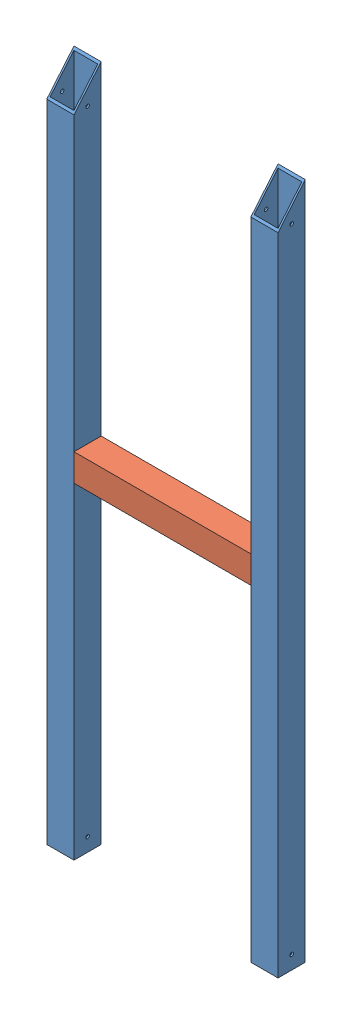
SolidWorks assembly GE-18077, configuration Default. Lengths in mm.
Overall size (431.8 1265.65 50.8).
3 component instances, 2 part files, 9 mates.
Components (placement in the parent):
- GE-18077-1-1: GE-18077-1 [Default] at (381 1434.7107 -127) x (0 -1 0) z (0 0 1) size (1265.65 50.8 50.8)
- GE-18077-1-2: GE-18077-1 [Default] at (0 1434.7107 -127) x (0 -1 0) z (0 0 1) size (1265.65 50.8 50.8)
- GE-18077-2-1: GE-18077-2 [Default] at (0 1434.7107 -127) x (0 -1 0) z (0 0 1) size (50.8 330.2 50.8)
Mates (geometry in assembly coordinates):
- Distance1: distance = 609.6 mm aligned: plane of GE-18077-2-1 through (165.1 609.6 25.4) normal (0 -1 0); plane of GE-18077-1-2 through (-215.9 0 1029.6131) normal (0 -1 0)
- Coincident2: coincident aligned: plane of GE-18077-1-2 through (-215.9 951.4898 50.8) normal (0 0 1); plane of GE-18077-2-1 through (165.1 951.4898 50.8) normal (0 0 1)
- Coincident3: coincident anti-aligned: plane of GE-18077-1-2 through (-165.1 933.0531 510.6552) normal (1 0 0); plane of GE-18077-2-1 through (-165.1 836.2206 25.4) normal (-1 0 0)
- Coincident4: coincident anti-aligned: plane of GE-18077-1-1 through (165.1 933.0531 510.6552) normal (-1 0 0); plane of GE-18077-2-1 through (165.1 836.2206 25.4) normal (1 0 0)
- Coincident5: coincident aligned: plane of GE-18077-1-1 through (165.1 951.4898 50.8) normal (0 0 1); plane of GE-18077-2-1 through (165.1 951.4898 50.8) normal (0 0 1)
- Coincident6: coincident aligned: plane of GE-18077-1-1 through (165.1 203.3958 1029.6131) normal (0 -1 0); plane of GE-18077-1-2 through (-215.9 203.3958 1029.6131) normal (0 -1 0)
- Coincident7: coincident anti-aligned: plane of ? through (-215.9 773.529 0) normal (0 0 -1)
- Coincident8: coincident aligned: plane of ? through (0 1434.7107 -127) normal (1 0 0)
- Coincident9: coincident anti-aligned: plane of GE-18077-1-1 through (165.1 0 1029.6131) normal (0 -1 0); plane of assembly
